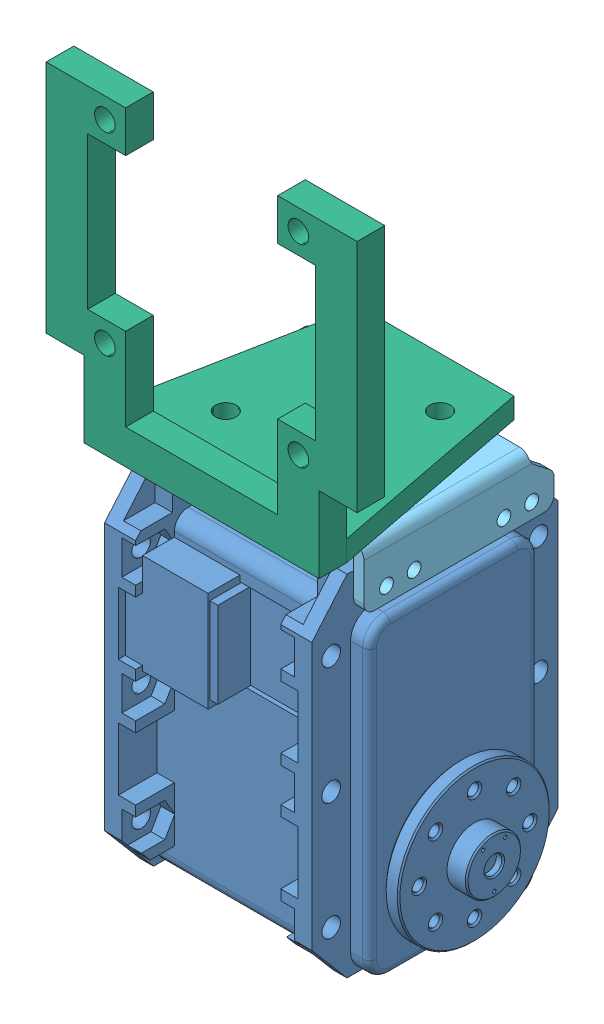
SolidWorks assembly head_2_no_camera, configuration Default. Lengths in mm.
Overall size (46.1 99.64 43.34).
6 component instances, 6 part files, 12 mates.
Components (placement in the parent):
- MX28_step-1: MX28_step [Default] at (-26.9298 -63.9825 50.4384) x (0 0 1) z (1 0 0) size (35.6 50.71 42.6)
- MX28_HN07-i101-1: MX28_HN07-i101 [Default] at (-4.5387 -101.2764 62.3462) x (0 0.153917 -0.988084) z (0 0.988084 0.153917) size (22 3.05 22)
- MF106ZZ-1: MF106ZZ [Défaut] at (-4.3887 -101.2764 62.3462) x (0 0.577041 0.816715) z (0 0.816715 -0.577041) size (11.2 3 11.2)
- RX28-CAP-1: RX28-CAP [Défaut] at (-4.3887 -101.2764 62.3462) x (0 1 0) z (-1 0 0) size (7.2 7.2 1.8)
- FR07-S101K-1: FR07-S101K [Default] at (15.6613 -60.4964 62.0962) x (-1 0 0) z (0 1 0) size (33 27.5 8.5)
- camera_supporter-1: camera_supporter [Default] at (15.6613 -31.1964 77.0962) size (45 45 43.34)
Mates (geometry in assembly coordinates):
- Concentric15: concentric aligned: cylinder of MX28_HN07-i101-1 through (-4.6912 -101.2764 62.3462) axis (1 0 0) radius 5; cylinder of MF106ZZ-1 through (-4.3887 -101.2764 62.3462) axis (1 0 0) radius 5
- Coincident16: coincident anti-aligned: plane of MX28_HN07-i101-1 through (-3.7887 -101.2764 62.3462) normal (-1 0 0); plane of MF106ZZ-1 through (-3.7887 -98.3912 66.4298) normal (1 0 0)
- Concentric16: concentric anti-aligned: cylinder of MF106ZZ-1 through (-4.3887 -101.2764 62.3462) axis (1 0 0) radius 3; cylinder of RX28-CAP-1 through (-3.3887 -101.2764 62.3462) axis (-1 0 0) radius 3
- Coincident17: coincident anti-aligned: plane of MF106ZZ-1 through (-4.3887 -98.0449 66.9198) normal (-1 0 0); plane of RX28-CAP-1 through (-4.3887 -97.7764 62.3462) normal (1 0 0)
- Concentric17: concentric anti-aligned: cylinder of MX28_step-1 through (16.6238 -101.2764 62.3462) axis (-1 0 0) radius 3; cylinder of MX28_HN07-i101-1 through (-4.6912 -101.2764 62.3462) axis (1 0 0) radius 6.25
- Coincident25: coincident anti-aligned: plane of MX28_step-1 through (-1.3887 -101.2764 62.3462) normal (-1 0 0); plane of MF106ZZ-1 through (-1.3887 -99.5452 64.7964) normal (1 0 0)
- Concentric18: concentric aligned: cylinder of MX28_step-1 through (15.6613 -65.4764 70.8462) axis (-1 0 0) radius 1.35; cylinder of FR07-S101K-1 through (0.6613 -65.4764 70.8462) axis (-1 0 0) radius 1
- Concentric19: concentric anti-aligned: cylinder of MX28_step-1 through (15.6613 -65.4764 53.8462) axis (-1 0 0) radius 1.35; cylinder of FR07-S101K-1 through (30.6613 -65.4764 53.8462) axis (1 0 0) radius 1
- Coincident26: coincident anti-aligned: plane of MX28_step-1 through (30.6613 -101.2764 62.3462) normal (1 0 0); plane of FR07-S101K-1 through (30.6613 -60.4964 62.0962) normal (-1 0 0)
- Concentric20: concentric anti-aligned: cylinder of FR07-S101K-1 through (7.9113 -59.1964 69.8462) axis (0 -1 0) radius 1; cylinder of camera_supporter-1 through (7.9113 -56.1964 69.8462) axis (0 1 0) radius 1.5
- Concentric21: concentric anti-aligned: cylinder of FR07-S101K-1 through (23.4113 -59.1964 54.3462) axis (0 -1 0) radius 1; cylinder of camera_supporter-1 through (23.4113 -56.1964 54.3462) axis (0 1 0) radius 1.5
- Coincident29: coincident anti-aligned: plane of FR07-S101K-1 through (15.6613 -59.1964 62.0962) normal (0 1 0); plane of camera_supporter-1 through (-1.3387 -59.1964 81.0962) normal (0 -1 0)
